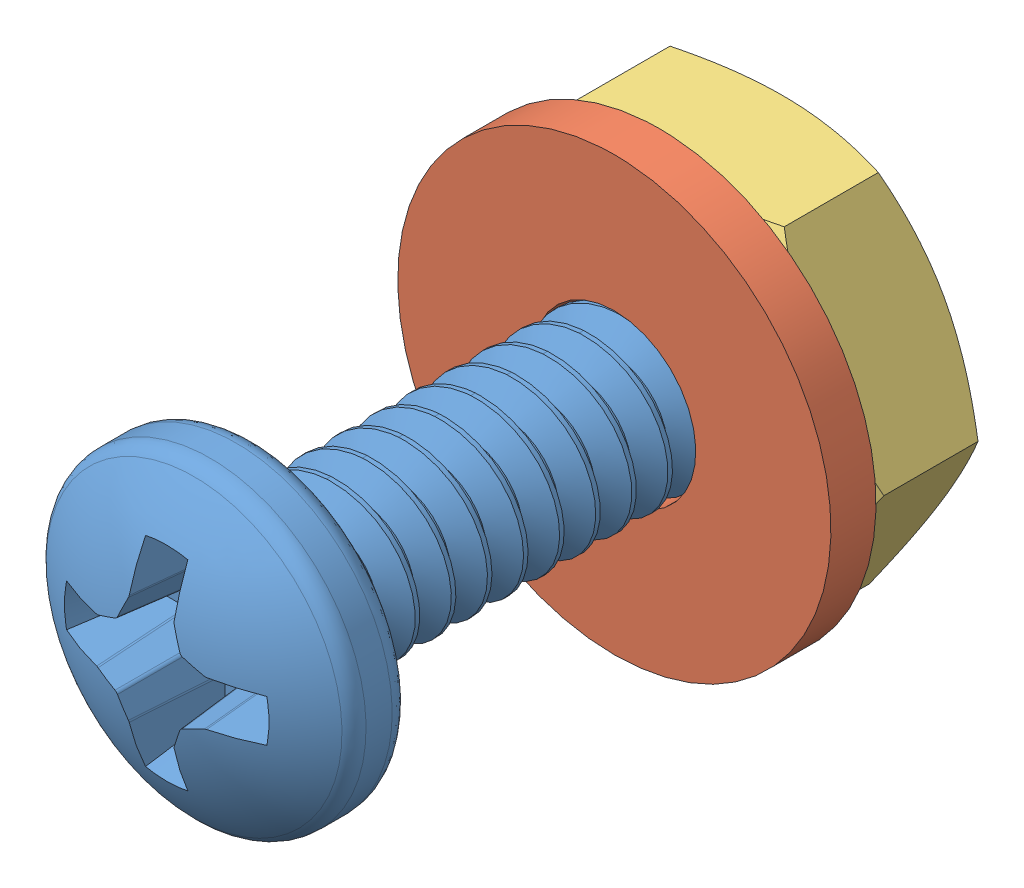
SolidWorks assembly 6-32 x 0.5in Screw Assy, configuration Default. Lengths in mm.
Overall size (11.55 11.96 15.21).
3 component instances, 3 part files, 5 mates.
Components (placement in the parent):
- 6-32 x 0.5in Screw-1: 6-32 x 0.5in Screw [90234A210] at origin size (6.86 6.86 15.21)
- 6-32 Washer-1: 6-32 Washer [96765A115] at (0 0 4.83) x (1 0 0) z (0 1 0) size (9.53 0.99 9.53)
- 6-32 Nut-1: 6-32 Nut [90545A007] at (0 0 2.4503) x (0.853185 -0.521608 0) z (0.521608 0.853185 0) size (7.94 3.39 9.17)
Mates (geometry in assembly coordinates):
- Concentric1: concentric: circle of 6-32 x 0.5in Screw-1; circle of 6-32 Washer-1
- Coincident2: coincident: line of 6-32 x 0.5in Screw-1 through (0 0 -3.2295) axis (0 0 1); line of 6-32 Nut-1 through (0 0 -3.1988) axis (0 0 -1)
- Screw1: screw = 1: line of 6-32 x 0.5in Screw-1 through (0 0 -3.2295) axis (0 0 1); line of 6-32 Nut-1 through (0 0 -3.1988) axis (0 0 -1)
- Coincident3: coincident: plane of 6-32 Washer-1 through (0 0 -3.682) normal (0 0 -1); plane of 6-32 Nut-1 through (4.5244 -0.7289 -3.682) normal (0 0 1)
- Distance1: distance = 7.87 mm: plane of 6-32 x 0.5in Screw-1 through (0 0 12.7) normal (0 0 -1); plane of 6-32 Washer-1 through (0 0 4.83) normal (0 0 1)
